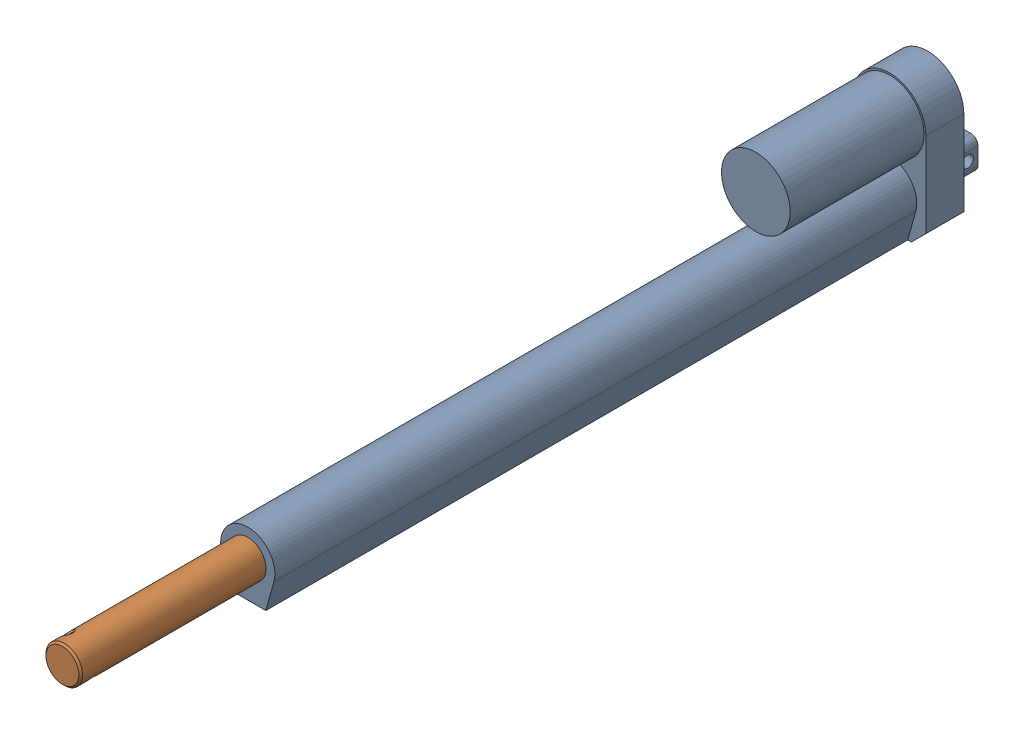
SolidWorks assembly Final1masterActuator_Assembly, configuration Default. Lengths in mm.
Overall size (40 75 497.7).
2 component instances, 2 part files, 2 mates.
Components (placement in the parent):
- Final1masterActuator_Body-1: Final1masterActuator_Body [Default] at (89.6726 206.5505 155.2608) size (40 75 395.2)
- Final1masterActuator_Shaft-1: Final1masterActuator_Shaft [Default] at (89.6726 189.0505 310.4608) x (-0.596785 0.802402 0) z (0 0 1) size (20.2 20.2 323.3)
Mates (geometry in assembly coordinates):
- Concentric1: concentric aligned: circle of masterActuator_Body-1; circle of masterActuator_Shaft-1
- LimitDistance1: limit distance = 33.1 mm aligned: plane of masterActuator_Shaft-1 through (89.6726 189.0505 633.7608) normal (0 0 1); plane of masterActuator_Body-1 through (89.6726 189.0505 531.2608) normal (0 0 1)
